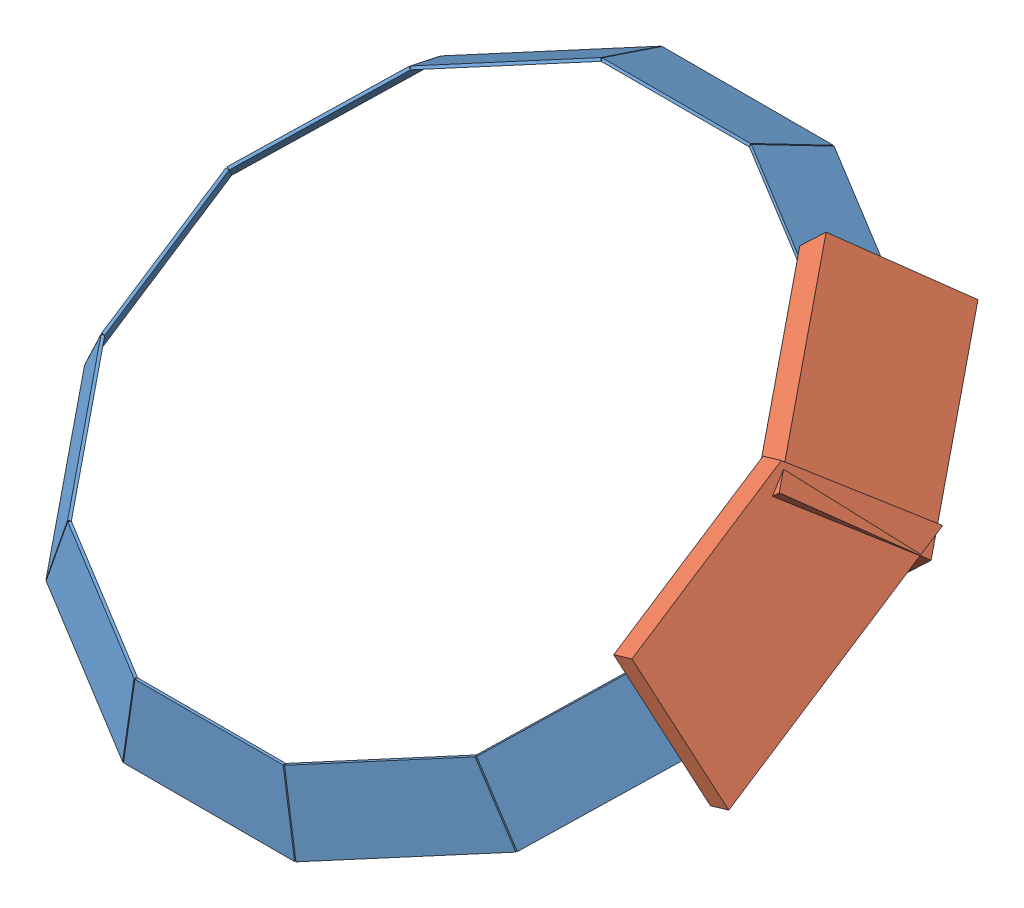
SolidWorks assembly Assembled, configuration Default. Lengths in mm.
Overall size (234.47 127.11 160.26).
97 component instances, 2 part files, 37 mates.
Components (placement in the parent):
- Panels-1: Panels [Default] at (-385.9053 -7.5706 477.2243) size (50.47 23 0.8)
- Panels-2: Panels [Default] at (-429.6136 6.2081 456.0831) x (0.866025 -0.273008 0.418888) z (-0.418888 0.061285 0.905968) size (50.47 23 0.8)
- Panels-3: Panels [Default] at (-454.8486 30.0735 419.4653) x (0.5 -0.472863 0.725535) z (-0.725535 0.228719 0.649066) size (50.47 23 0.8)
- Panels-4: Panels [Default] at (-454.8486 57.6309 377.1828) x (0 -0.546015 0.837775) z (-0.837775 0.457438 0.298133) size (50.47 23 0.8)
- Panels-5: Panels [Default] at (-335.4353 -7.5706 477.2243) x (0.866025 0.273008 -0.418888) z (0.418888 0.061285 0.905968) size (50.47 23 0.8)
- Panels-6: Panels [Default] at (-265.9116 30.2565 419.9846) x (-0.5 -0.472863 0.725535) z (-0.725535 -0.228719 -0.649066) size (50.47 23 0.8)
- Panels-7: Panels [Default] at (-455.4291 58.1798 377.1406) x (0.5 0.472863 -0.725535) z (0.725535 -0.686157 0.052801) size (50.47 23 0.8)
- Panels-8: Panels [Default] at (-385.9053 95.275 319.4238) x (-0.866025 -0.273008 0.418888) z (-0.418888 0.853591 -0.309702) size (50.47 23 0.8)
- Panels-9: Panels [Default] at (-335.1002 95.9578 319.1761) x (0.866025 -0.273008 0.418888) z (-0.418888 -0.853591 0.309702) size (50.47 23 0.8)
- Panels-10: Panels [Default] at (-335.4353 95.275 319.4238) x (-1 0 0) z (0 0.914876 -0.403735) size (50.47 23 0.8)
- Panels-11: Panels [Default] at (-291.1466 82.0452 340.5228) x (0.5 -0.472863 0.725535) z (-0.725535 -0.686157 0.052801) size (50.47 23 0.8)
- Panels-12: Panels [Default] at (-265.8218 57.9968 377.4213) x (0 -0.546015 0.837775) z (-0.837775 -0.457438 -0.298133) size (50.47 23 0.8)
- Panels-13: Panels [Default] at (-455.4291 74.9353 388.0609) x (0.5 0.472863 -0.725535) z (0.725535 -0.686157 0.052801) size (50.47 23 0.8) (suppressed, hidden)
- Panels-14: Panels [Default] at (-455.4291 91.6908 398.9812) x (0.5 0.472863 -0.725535) z (0.725535 -0.686157 0.052801) size (50.47 23 0.8) (suppressed, hidden)
- Panels-15: Panels [Default] at (-455.4291 108.4463 409.9015) x (0.5 0.472863 -0.725535) z (0.725535 -0.686157 0.052801) size (50.47 23 0.8) (suppressed, hidden)
- Panels-16: Panels [Default] at (-385.9053 112.0305 330.3441) x (-0.866025 -0.273008 0.418888) z (-0.418888 0.853591 -0.309702) size (50.47 23 0.8) (suppressed, hidden)
- Panels-17: Panels [Default] at (-385.9053 128.786 341.2644) x (-0.866025 -0.273008 0.418888) z (-0.418888 0.853591 -0.309702) size (50.47 23 0.8) (suppressed, hidden)
- Panels-18: Panels [Default] at (-385.9053 145.5415 352.1847) x (-0.866025 -0.273008 0.418888) z (-0.418888 0.853591 -0.309702) size (50.47 23 0.8) (suppressed, hidden)
- Panels-19: Panels [Default] at (-291.1466 98.8007 351.4432) x (0.5 -0.472863 0.725535) z (-0.725535 -0.686157 0.052801) size (50.47 23 0.8) (suppressed, hidden)
- Panels-20: Panels [Default] at (-291.1466 115.5562 362.3635) x (0.5 -0.472863 0.725535) z (-0.725535 -0.686157 0.052801) size (50.47 23 0.8) (suppressed, hidden)
- Panels-21: Panels [Default] at (-291.1466 132.3117 373.2838) x (0.5 -0.472863 0.725535) z (-0.725535 -0.686157 0.052801) size (50.47 23 0.8) (suppressed, hidden)
- Panels-22: Panels [Default] at (-335.1002 112.7133 330.0964) x (0.866025 -0.273008 0.418888) z (-0.418888 -0.853591 0.309702) size (50.47 23 0.8) (suppressed, hidden)
- Panels-23: Panels [Default] at (-335.1002 129.4689 341.0167) x (0.866025 -0.273008 0.418888) z (-0.418888 -0.853591 0.309702) size (50.47 23 0.8) (suppressed, hidden)
- Panels-24: Panels [Default] at (-335.1002 146.2244 351.937) x (0.866025 -0.273008 0.418888) z (-0.418888 -0.853591 0.309702) size (50.47 23 0.8) (suppressed, hidden)
- Panels-25: Panels [Default] at (-265.8218 74.7523 388.3416) x (0 -0.546015 0.837775) z (-0.837775 -0.457438 -0.298133) size (50.47 23 0.8) (suppressed, hidden)
- Panels-26: Panels [Default] at (-265.8218 91.5078 399.2619) x (0 -0.546015 0.837775) z (-0.837775 -0.457438 -0.298133) size (50.47 23 0.8) (suppressed, hidden)
- Panels-27: Panels [Default] at (-265.8218 108.2633 410.1822) x (0 -0.546015 0.837775) z (-0.837775 -0.457438 -0.298133) size (50.47 23 0.8) (suppressed, hidden)
- Panels-28: Panels [Default] at (-335.4353 112.0305 330.3441) x (-1 0 0) z (0 0.914876 -0.403735) size (50.47 23 0.8) (suppressed, hidden)
- Panels-29: Panels [Default] at (-335.4353 128.786 341.2644) x (-1 0 0) z (0 0.914876 -0.403735) size (50.47 23 0.8) (suppressed, hidden)
- Panels-30: Panels [Default] at (-335.4353 145.5415 352.1847) x (-1 0 0) z (0 0.914876 -0.403735) size (50.47 23 0.8) (suppressed, hidden)
- Panels-31: Panels [Default] at (-265.9116 47.012 430.9049) x (-0.5 -0.472863 0.725535) z (-0.725535 -0.228719 -0.649066) size (50.47 23 0.8) (suppressed, hidden)
- Panels-32: Panels [Default] at (-265.9116 63.7675 441.8252) x (-0.5 -0.472863 0.725535) z (-0.725535 -0.228719 -0.649066) size (50.47 23 0.8) (suppressed, hidden)
- Panels-33: Panels [Default] at (-265.9116 80.523 452.7455) x (-0.5 -0.472863 0.725535) z (-0.725535 -0.228719 -0.649066) size (50.47 23 0.8) (suppressed, hidden)
- Panels-34: Panels [Default] at (-429.6136 22.9636 467.0034) x (0.866025 -0.273008 0.418888) z (-0.418888 0.061285 0.905968) size (50.47 23 0.8) (suppressed, hidden)
- Panels-35: Panels [Default] at (-429.6136 39.7191 477.9237) x (0.866025 -0.273008 0.418888) z (-0.418888 0.061285 0.905968) size (50.47 23 0.8) (suppressed, hidden)
- Panels-36: Panels [Default] at (-429.6136 56.4746 488.844) x (0.866025 -0.273008 0.418888) z (-0.418888 0.061285 0.905968) size (50.47 23 0.8) (suppressed, hidden)
- Panels-37: Panels [Default] at (-335.4353 9.1849 488.1446) x (0.866025 0.273008 -0.418888) z (0.418888 0.061285 0.905968) size (50.47 23 0.8) (suppressed, hidden)
- Panels-38: Panels [Default] at (-335.4353 25.9404 499.0649) x (0.866025 0.273008 -0.418888) z (0.418888 0.061285 0.905968) size (50.47 23 0.8) (suppressed, hidden)
- Panels-39: Panels [Default] at (-335.4353 42.6959 509.9852) x (0.866025 0.273008 -0.418888) z (0.418888 0.061285 0.905968) size (50.47 23 0.8) (suppressed, hidden)
- Panels-40: Panels [Default] at (-454.8486 74.3864 388.1031) x (0 -0.546015 0.837775) z (-0.837775 0.457438 0.298133) size (50.47 23 0.8) (suppressed, hidden)
- Panels-41: Panels [Default] at (-454.8486 91.1419 399.0234) x (0 -0.546015 0.837775) z (-0.837775 0.457438 0.298133) size (50.47 23 0.8) (suppressed, hidden)
- Panels-42: Panels [Default] at (-454.8486 107.8974 409.9437) x (0 -0.546015 0.837775) z (-0.837775 0.457438 0.298133) size (50.47 23 0.8) (suppressed, hidden)
- Panels-43: Panels [Default] at (-454.8486 46.829 430.3856) x (0.5 -0.472863 0.725535) z (-0.725535 0.228719 0.649066) size (50.47 23 0.8) (suppressed, hidden)
- Panels-44: Panels [Default] at (-454.8486 63.5845 441.3059) x (0.5 -0.472863 0.725535) z (-0.725535 0.228719 0.649066) size (50.47 23 0.8) (suppressed, hidden)
- Panels-45: Panels [Default] at (-454.8486 80.34 452.2263) x (0.5 -0.472863 0.725535) z (-0.725535 0.228719 0.649066) size (50.47 23 0.8) (suppressed, hidden)
- Panels-46: Panels [Default] at (-385.9053 9.1849 488.1446) size (50.47 23 0.8) (suppressed, hidden)
- Panels-47: Panels [Default] at (-385.9053 25.9404 499.0649) size (50.47 23 0.8) (suppressed, hidden)
- Panels-48: Panels [Default] at (-385.9053 42.6959 509.9852) size (50.47 23 0.8) (suppressed, hidden)
- Panels-49: Panels [Default] at (-385.9053 59.4514 520.9055) size (50.47 23 0.8) (suppressed, hidden)
- Panels-50: Panels [Default] at (-385.9053 76.2069 531.8259) size (50.47 23 0.8) (suppressed, hidden)
- Panels-51: Panels [Default] at (-385.9053 92.9624 542.7462) size (50.47 23 0.8) (suppressed, hidden)
- Panels-52: Panels [Default] at (-385.9053 109.7179 553.6665) size (50.47 23 0.8) (suppressed, hidden)
- Panels-53: Panels [Default] at (-454.8486 97.0955 463.1466) x (0.5 -0.472863 0.725535) z (-0.725535 0.228719 0.649066) size (50.47 23 0.8) (suppressed, hidden)
- Panels-54: Panels [Default] at (-454.8486 113.851 474.0669) x (0.5 -0.472863 0.725535) z (-0.725535 0.228719 0.649066) size (50.47 23 0.8) (suppressed, hidden)
- Panels-55: Panels [Default] at (-454.8486 130.6065 484.9872) x (0.5 -0.472863 0.725535) z (-0.725535 0.228719 0.649066) size (50.47 23 0.8) (suppressed, hidden)
- Panels-56: Panels [Default] at (-454.8486 147.362 495.9075) x (0.5 -0.472863 0.725535) z (-0.725535 0.228719 0.649066) size (50.47 23 0.8) (suppressed, hidden)
- Panels-57: Panels [Default] at (-454.8486 124.6529 420.864) x (0 -0.546015 0.837775) z (-0.837775 0.457438 0.298133) size (50.47 23 0.8) (suppressed, hidden)
- Panels-58: Panels [Default] at (-454.8486 141.4084 431.7843) x (0 -0.546015 0.837775) z (-0.837775 0.457438 0.298133) size (50.47 23 0.8) (suppressed, hidden)
- Panels-59: Panels [Default] at (-454.8486 158.1639 442.7047) x (0 -0.546015 0.837775) z (-0.837775 0.457438 0.298133) size (50.47 23 0.8) (suppressed, hidden)
- Panels-60: Panels [Default] at (-454.8486 174.9194 453.625) x (0 -0.546015 0.837775) z (-0.837775 0.457438 0.298133) size (50.47 23 0.8) (suppressed, hidden)
- Panels-61: Panels [Default] at (-335.4353 59.4514 520.9055) x (0.866025 0.273008 -0.418888) z (0.418888 0.061285 0.905968) size (50.47 23 0.8) (suppressed, hidden)
- Panels-62: Panels [Default] at (-335.4353 76.2069 531.8259) x (0.866025 0.273008 -0.418888) z (0.418888 0.061285 0.905968) size (50.47 23 0.8) (suppressed, hidden)
- Panels-63: Panels [Default] at (-335.4353 92.9624 542.7462) x (0.866025 0.273008 -0.418888) z (0.418888 0.061285 0.905968) size (50.47 23 0.8) (suppressed, hidden)
- Panels-64: Panels [Default] at (-335.4353 109.7179 553.6665) x (0.866025 0.273008 -0.418888) z (0.418888 0.061285 0.905968) size (50.47 23 0.8) (suppressed, hidden)
- Panels-65: Panels [Default] at (-429.6136 73.2301 499.7643) x (0.866025 -0.273008 0.418888) z (-0.418888 0.061285 0.905968) size (50.47 23 0.8) (suppressed, hidden)
- Panels-66: Panels [Default] at (-429.6136 89.9856 510.6846) x (0.866025 -0.273008 0.418888) z (-0.418888 0.061285 0.905968) size (50.47 23 0.8) (suppressed, hidden)
- Panels-67: Panels [Default] at (-429.6136 106.7411 521.6049) x (0.866025 -0.273008 0.418888) z (-0.418888 0.061285 0.905968) size (50.47 23 0.8) (suppressed, hidden)
- Panels-68: Panels [Default] at (-429.6136 123.4966 532.5252) x (0.866025 -0.273008 0.418888) z (-0.418888 0.061285 0.905968) size (50.47 23 0.8) (suppressed, hidden)
- Panels-69: Panels [Default] at (-265.9116 97.2785 463.6658) x (-0.5 -0.472863 0.725535) z (-0.725535 -0.228719 -0.649066) size (50.47 23 0.8) (suppressed, hidden)
- Panels-70: Panels [Default] at (-265.9116 114.034 474.5861) x (-0.5 -0.472863 0.725535) z (-0.725535 -0.228719 -0.649066) size (50.47 23 0.8) (suppressed, hidden)
- Panels-71: Panels [Default] at (-265.9116 130.7895 485.5064) x (-0.5 -0.472863 0.725535) z (-0.725535 -0.228719 -0.649066) size (50.47 23 0.8) (suppressed, hidden)
- Panels-72: Panels [Default] at (-265.9116 147.545 496.4267) x (-0.5 -0.472863 0.725535) z (-0.725535 -0.228719 -0.649066) size (50.47 23 0.8) (suppressed, hidden)
- Panels-73: Panels [Default] at (-335.4353 162.297 363.1051) x (-1 0 0) z (0 0.914876 -0.403735) size (50.47 23 0.8) (suppressed, hidden)
- Panels-74: Panels [Default] at (-335.4353 179.0525 374.0254) x (-1 0 0) z (0 0.914876 -0.403735) size (50.47 23 0.8) (suppressed, hidden)
- Panels-75: Panels [Default] at (-335.4353 195.808 384.9457) x (-1 0 0) z (0 0.914876 -0.403735) size (50.47 23 0.8) (suppressed, hidden)
- Panels-76: Panels [Default] at (-335.4353 212.5635 395.866) x (-1 0 0) z (0 0.914876 -0.403735) size (50.47 23 0.8) (suppressed, hidden)
- Panels-77: Panels [Default] at (-265.8218 125.0188 421.1025) x (0 -0.546015 0.837775) z (-0.837775 -0.457438 -0.298133) size (50.47 23 0.8) (suppressed, hidden)
- Panels-78: Panels [Default] at (-265.8218 141.7743 432.0229) x (0 -0.546015 0.837775) z (-0.837775 -0.457438 -0.298133) size (50.47 23 0.8) (suppressed, hidden)
- Panels-79: Panels [Default] at (-265.8218 158.5299 442.9432) x (0 -0.546015 0.837775) z (-0.837775 -0.457438 -0.298133) size (50.47 23 0.8) (suppressed, hidden)
- Panels-80: Panels [Default] at (-265.8218 175.2854 453.8635) x (0 -0.546015 0.837775) z (-0.837775 -0.457438 -0.298133) size (50.47 23 0.8) (suppressed, hidden)
- Panels-81: Panels [Default] at (-335.1002 162.9799 362.8573) x (0.866025 -0.273008 0.418888) z (-0.418888 -0.853591 0.309702) size (50.47 23 0.8) (suppressed, hidden)
- Panels-82: Panels [Default] at (-335.1002 179.7354 373.7776) x (0.866025 -0.273008 0.418888) z (-0.418888 -0.853591 0.309702) size (50.47 23 0.8) (suppressed, hidden)
- Panels-83: Panels [Default] at (-335.1002 196.4909 384.6979) x (0.866025 -0.273008 0.418888) z (-0.418888 -0.853591 0.309702) size (50.47 23 0.8) (suppressed, hidden)
- Panels-84: Panels [Default] at (-335.1002 213.2464 395.6182) x (0.866025 -0.273008 0.418888) z (-0.418888 -0.853591 0.309702) size (50.47 23 0.8) (suppressed, hidden)
- Panels-85: Panels [Default] at (-291.1466 149.0672 384.2041) x (0.5 -0.472863 0.725535) z (-0.725535 -0.686157 0.052801) size (50.47 23 0.8) (suppressed, hidden)
- Panels-86: Panels [Default] at (-291.1466 165.8227 395.1244) x (0.5 -0.472863 0.725535) z (-0.725535 -0.686157 0.052801) size (50.47 23 0.8) (suppressed, hidden)
- Panels-87: Panels [Default] at (-291.1466 182.5782 406.0447) x (0.5 -0.472863 0.725535) z (-0.725535 -0.686157 0.052801) size (50.47 23 0.8) (suppressed, hidden)
- Panels-88: Panels [Default] at (-291.1466 199.3337 416.965) x (0.5 -0.472863 0.725535) z (-0.725535 -0.686157 0.052801) size (50.47 23 0.8) (suppressed, hidden)
- Panels-89: Panels [Default] at (-385.9053 162.297 363.1051) x (-0.866025 -0.273008 0.418888) z (-0.418888 0.853591 -0.309702) size (50.47 23 0.8) (suppressed, hidden)
- Panels-90: Panels [Default] at (-385.9053 179.0525 374.0254) x (-0.866025 -0.273008 0.418888) z (-0.418888 0.853591 -0.309702) size (50.47 23 0.8) (suppressed, hidden)
- Panels-91: Panels [Default] at (-385.9053 195.808 384.9457) x (-0.866025 -0.273008 0.418888) z (-0.418888 0.853591 -0.309702) size (50.47 23 0.8) (suppressed, hidden)
- Panels-92: Panels [Default] at (-385.9053 212.5635 395.866) x (-0.866025 -0.273008 0.418888) z (-0.418888 0.853591 -0.309702) size (50.47 23 0.8) (suppressed, hidden)
- Panels-93: Panels [Default] at (-455.4291 125.2018 420.8218) x (0.5 0.472863 -0.725535) z (0.725535 -0.686157 0.052801) size (50.47 23 0.8) (suppressed, hidden)
- Panels-94: Panels [Default] at (-455.4291 141.9573 431.7421) x (0.5 0.472863 -0.725535) z (0.725535 -0.686157 0.052801) size (50.47 23 0.8) (suppressed, hidden)
- Panels-95: Panels [Default] at (-455.4291 158.7128 442.6624) x (0.5 0.472863 -0.725535) z (0.725535 -0.686157 0.052801) size (50.47 23 0.8) (suppressed, hidden)
- Panels-96: Panels [Default] at (-455.4291 175.4683 453.5827) x (0.5 0.472863 -0.725535) z (0.725535 -0.686157 0.052801) size (50.47 23 0.8) (suppressed, hidden)
- PanelHolder^Assembled-1: PanelHolder^Assembled [Default] at (-291.1466 82.0452 340.5228) x (-0.5 0.472863 -0.725535) z (0.725535 0.686157 -0.052801) size (119.68 54.28 40.63) (virtual)
Mates (geometry in assembly coordinates):
- Coincident1: coincident: line of Panels-1 through (-335.4353 -7.5706 477.2243) axis (-0.144763 0.989466 0); line of Panels-5 through (-338.8003 15.4294 477.2243) axis (0.144763 -0.989466 0)
- Coincident3: coincident: point of Panels-1; point of Panels-5
- Coincident5: coincident: line of Panels-5 through (-291.727 6.2081 456.0831) axis (-0.3955 0.910423 0.121279); line of Panels-6 through (-291.727 6.2081 456.0831) axis (-0.3955 0.910423 0.121279)
- Coincident6: coincident: point of Panels-5; point of Panels-6
- Angle1: planar angle = 2.617994 rad: line of Panels-5 through (-300.9204 27.3707 458.9022) axis (-0.866025 -0.273008 0.418888); line of Panels-6 through (-300.9204 27.3707 458.9022) axis (0.5 0.472863 -0.725535)
- Angle2: planar angle = 2.617994 rad: line of Panels-1 through (-338.8003 15.4294 477.2243) axis (-1 0 0); line of Panels-5 through (-300.9204 27.3707 458.9022) axis (-0.866025 -0.273008 0.418888)
- Coincident8: coincident: line of Panels-1 through (-382.5403 15.4294 477.2243) axis (-0.144763 -0.989466 0); line of Panels-2 through (-385.9053 -7.5706 477.2243) axis (0.144763 0.989466 0)
- Coincident9: coincident: point of Panels-1; point of Panels-2
- Angle3: planar angle = 2.617994 rad: line of Panels-2 through (-382.5403 15.4294 477.2243) axis (-0.866025 0.273008 -0.418888); line of Panels-1 through (-338.8003 15.4294 477.2243) axis (-1 0 0)
- Coincident10: coincident: line of Panels-2 through (-420.4203 27.3707 458.9022) axis (-0.3955 -0.910423 -0.121279); line of Panels-3 through (-429.6136 6.2081 456.0831) axis (0.3955 0.910423 0.121279)
- Coincident11: coincident: point of Panels-2; point of Panels-3
- Angle5: planar angle = 2.617994 rad: line of Panels-3 through (-420.4203 27.3707 458.9022) axis (-0.5 0.472863 -0.725535); line of Panels-2 through (-382.5403 15.4294 477.2243) axis (-0.866025 0.273008 -0.418888)
- Coincident13: coincident: line of Panels-3 through (-442.2903 48.0538 427.1673) axis (-0.540264 -0.773517 -0.331341); line of Panels-4 through (-454.8486 30.0735 419.4653) axis (0.540264 0.773517 0.331341)
- Coincident14: coincident: point of Panels-3; point of Panels-4
- Angle6: planar angle = 2.617994 rad: line of Panels-3 through (-420.4203 27.3707 458.9022) axis (-0.5 0.472863 -0.725535); line of Panels-4 through (-442.2903 48.0538 427.1673) axis (0 0.546015 -0.837775)
- Coincident15: coincident: line of Panels-4 through (-442.2903 71.9365 390.523) axis (-0.540264 -0.615431 -0.573899); line of Panels-7 through (-442.2903 71.9365 390.523) axis (-0.540264 -0.615431 -0.573899)
- Coincident16: coincident: point of Panels-4; point of Panels-7
- Coincident17: coincident: line of Panels-6 through (-279.0504 48.0538 427.1673) axis (0.540264 -0.773517 -0.331341); line of Panels-12 through (-266.492 30.0735 419.4653) axis (-0.540264 0.773517 0.331341)
- Coincident18: coincident: point of Panels-6; point of Panels-12
- Angle7: planar angle = 2.617994 rad: line of Panels-6 through (-300.9204 27.3707 458.9022) axis (0.5 0.472863 -0.725535); line of Panels-12 through (-279.0504 48.0538 427.1673) axis (0 0.546015 -0.837775)
- Angle8: planar angle = 2.617994 rad: line of Panels-4 through (-442.2903 48.0538 427.1673) axis (0 0.546015 -0.837775); line of Panels-7 through (-420.4203 92.6195 358.7881) axis (-0.5 -0.472863 0.725535)
- Coincident21: coincident: point of Panels-7; point of Panels-8
- Coincident22: coincident: line of Panels-11 through (-266.492 57.6309 377.1828) axis (-0.540264 0.615431 0.573899); line of Panels-12 through (-279.0504 71.9365 390.523) axis (0.540264 -0.615431 -0.573899)
- Coincident23: coincident: point of Panels-11; point of Panels-12
- Angle10: planar angle = 2.617994 rad: line of Panels-12 through (-279.0504 48.0538 427.1673) axis (0 0.546015 -0.837775); line of Panels-11 through (-279.0504 71.9365 390.523) axis (-0.5 0.472863 -0.725535)
- Coincident25: coincident: line of Panels-9 through (-291.727 81.4963 340.5651) axis (-0.3955 0.478525 0.78396); line of Panels-11 through (-300.9204 92.6195 358.7881) axis (0.3955 -0.478525 -0.78396)
- Coincident26: coincident: point of Panels-9; point of Panels-11
- Coincident27: coincident: line of Panels-8 through (-382.5403 104.5609 340.466) axis (-0.144763 -0.399482 -0.905239); line of Panels-10 through (-385.9053 95.275 319.4238) axis (0.144763 0.399482 0.905239)
- Coincident29: coincident: point of Panels-8; point of Panels-10
- Angle11: planar angle = 2.617994 rad: line of Panels-8 through (-420.4203 92.6195 358.7881) axis (0.866025 0.273008 -0.418888); line of Panels-10 through (-382.5403 104.5609 340.466) axis (1 0 0)
- Angle12: planar angle = 2.617994 rad: line of Panels-9 through (-300.9204 92.6195 358.7881) axis (-0.866025 0.273008 -0.418888); line of Panels-11 through (-279.0504 71.9365 390.523) axis (-0.5 0.472863 -0.725535)
- Coincident34: coincident: line of Panels-7 through (-429.6136 81.4963 340.5651) axis (0.3955 0.478525 0.78396); line of Panels-8 through (-429.6136 81.4963 340.5651) axis (0.3955 0.478525 0.78396)
- Angle13: planar angle = 2.617994 rad: line of Panels-9 through (-300.9204 92.6195 358.7881) axis (-0.866025 0.273008 -0.418888); line of Panels-10 through (-382.5403 104.5609 340.466) axis (1 0 0)
- InPlace2: in place: plane of Panels-11 through (-291.1466 82.0452 340.5228) normal (0.725535 0.686157 -0.052801); plane of ? through (-125.4602 -118.651 9.1304) normal (0.725535 0.686157 -0.052801); moOrthogonalPlaneRef_w of Panels-11 through (-291.1466 82.0452 340.5228) normal (0.725535 0.686157 -0.052801); plane of ? through (-125.4602 -118.651 9.1304) normal (-0.687116 0.726548 0); plane of Panels-11 through (-291.1466 82.0452 340.5228) normal (0.725535 0.686157 -0.052801); plane of ? through (-125.4602 -118.651 9.1304) normal (-0.038362 -0.03628 -0.998605); plane of Panels-11 through (-291.1466 82.0452 340.5228) normal (0.725535 0.686157 -0.052801); unknown of PanelHolder^Assembled-1
- Coincident37: coincident: plane of Panels-11; plane of PanelHolder^Assembled-1
- Coincident38: coincident: moOrthogonalPlaneRef_w of Panels-11 through (-291.1466 82.0452 340.5228) normal (-0.472863 0.552801 0.686157); plane of PanelHolder^Assembled-1 through (-291.1466 82.0452 340.5228) normal (-0.472863 0.552801 0.686157)
- Coincident39: coincident: moOrthogonalPlaneRef_w of Panels-11 through (-291.1466 82.0452 340.5228) normal (0.5 -0.472863 0.725535); plane of PanelHolder^Assembled-1 through (-291.1466 82.0452 340.5228) normal (-0.5 0.472863 -0.725535)
